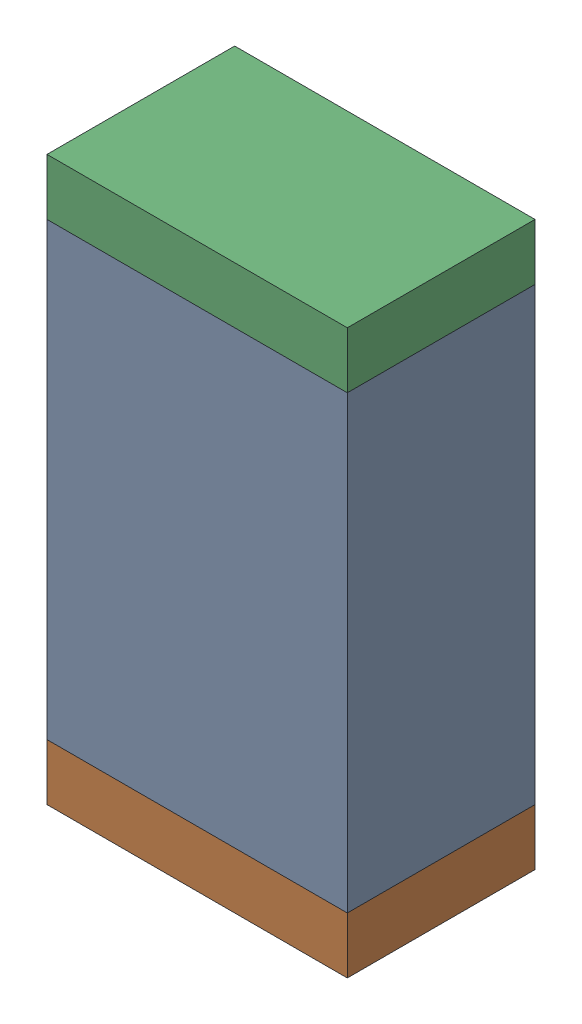
SolidWorks assembly R6, configuration Default. Lengths in mm.
Overall size (0.8 1.5 0.5).
6 component instances, 2 part files, 0 mates.
Components (placement in the parent):
- 810156976-1: 810156976 [Default] at (127 33.15 0) size (0.8 1.2 0.5)
  - Extruded_6-1: Extruded_6 [Default] at origin size (0.8 1.2 0.5)
- 810156592-1: 810156592 [Default] at (127 32.475 0) size (0.8 0.15 0.5)
  - Extruded_7-1: Extruded_7 [Default] at origin size (0.8 0.15 0.5)
- 810156592-2: 810156592 [Default] at (127 33.825 0) size (0.8 0.15 0.5)
  - Extruded_7-1: Extruded_7 [Default] at origin size (0.8 0.15 0.5)
